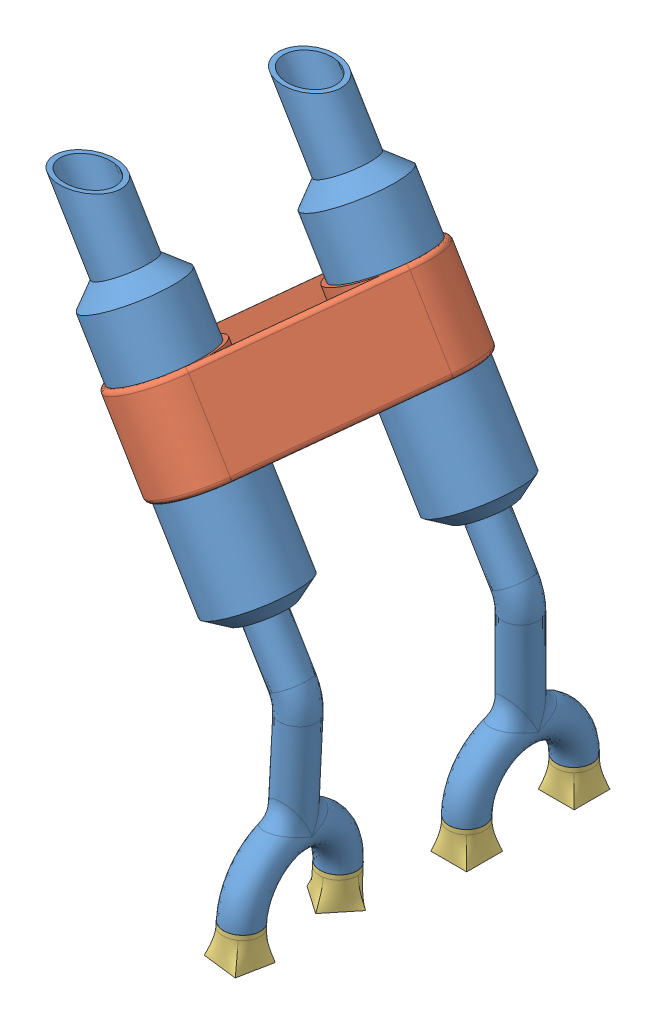
SolidWorks assembly Assem1, configuration Default. Lengths in mm.
Overall size (360.64 648.2 385).
7 component instances, 3 part files, 10 mates.
Components (placement in the parent):
- Exhaust pipe 2-1: Exhaust pipe 2 [Default] at (348.4875 55.2723 405.2786) size (292.83 573.09 160)
- Exhaust pipe holder-1: Exhaust pipe holder [Default] at (193.4761 426.8368 498.9783) x (0.299393 0.180003 -0.936997) z (0.515269 -0.857029 0) size (310 110 100)
- Exhaust pipe to engine connector-1: Exhaust pipe to engine connector [Default] at (294.444 -11.1557 664.7029) x (0.991874 0.009989 0.12683) z (-0.002734 0.998356 -0.057249) size (43.92 43.92 35.05)
- Exhaust pipe to engine connector-2: Exhaust pipe to engine connector [Default] at (283.0177 -18.0255 545.4459) x (0.577889 -0.045144 -0.814866) z (-0.002734 0.998356 -0.057249) size (43.92 43.92 35.05)
- Exhaust pipe to engine connector-3: Exhaust pipe to engine connector [Default] at (348.4875 20.2723 465.2786) x (1 0 0) z (0 1 0) size (43.92 43.92 35.05)
- Exhaust pipe to engine connector-4: Exhaust pipe to engine connector [Default] at (348.4875 20.2723 345.2786) x (1 0 0) z (0 1 0) size (43.92 43.92 35.05)
- Exhaust pipe 2-2: Exhaust pipe 2 [Default] at (288.6352 20.3519 603.0707) x (0.995453 -0.002734 -0.09522) z (0.09522 0.057249 0.993809) size (292.83 573.09 160)
Mates (geometry in assembly coordinates):
- Concentric1: concentric anti-aligned: cylinder of Exhaust pipe 2-1 through (155.3075 558.1184 405.2786) axis (0.515269 -0.857029 0) radius 50; cylinder of Exhaust pipe holder-1 through (249.1788 401.9857 405.2786) axis (-0.515269 0.857029 0) radius 50
- Concentric2: concentric anti-aligned: cylinder of Exhaust pipe holder-1 through (189.3002 365.9851 592.678) axis (-0.515269 0.857029 0) radius 50; cylinder of Exhaust pipe 2-2 through (94.9589 522.8997 592.678) axis (0.515269 -0.857029 0) radius 50
- Concentric3: concentric anti-aligned: circle of Exhaust pipe to engine connector-1; circle of Exhaust pipe 2-2
- Coincident6: coincident anti-aligned: plane of Exhaust pipe to engine connector-1 through (294.3484 23.7868 662.6992) normal (-0.002734 0.998356 -0.057249); circle of Exhaust pipe 2-2
- Coincident7: coincident anti-aligned: plane of Exhaust pipe to engine connector-2 through (282.922 16.917 543.4422) normal (-0.002734 0.998356 -0.057249); plane of Exhaust pipe 2-2 through (282.922 16.917 543.4422) normal (0.002734 -0.998356 0.057249)
- Concentric5: concentric aligned: circle of Exhaust pipe to engine connector-2; circle of Exhaust pipe 2-2
- Coincident10: coincident anti-aligned: plane of Exhaust pipe 2-1 through (348.4875 55.2723 465.2786) normal (0 -1 0); plane of Exhaust pipe to engine connector-4 through (348.4875 55.2723 345.2786) normal (0 1 0)
- Concentric6: concentric aligned: circle of Exhaust pipe 2-1; circle of Exhaust pipe to engine connector-4
- Coincident12: coincident anti-aligned: plane of Exhaust pipe 2-1 through (348.4875 55.2723 465.2786) normal (0 -1 0); plane of Exhaust pipe to engine connector-3 through (348.4875 55.2723 465.2786) normal (0 1 0)
- Concentric7: concentric anti-aligned: circle of Exhaust pipe 2-1; circle of Exhaust pipe to engine connector-3
